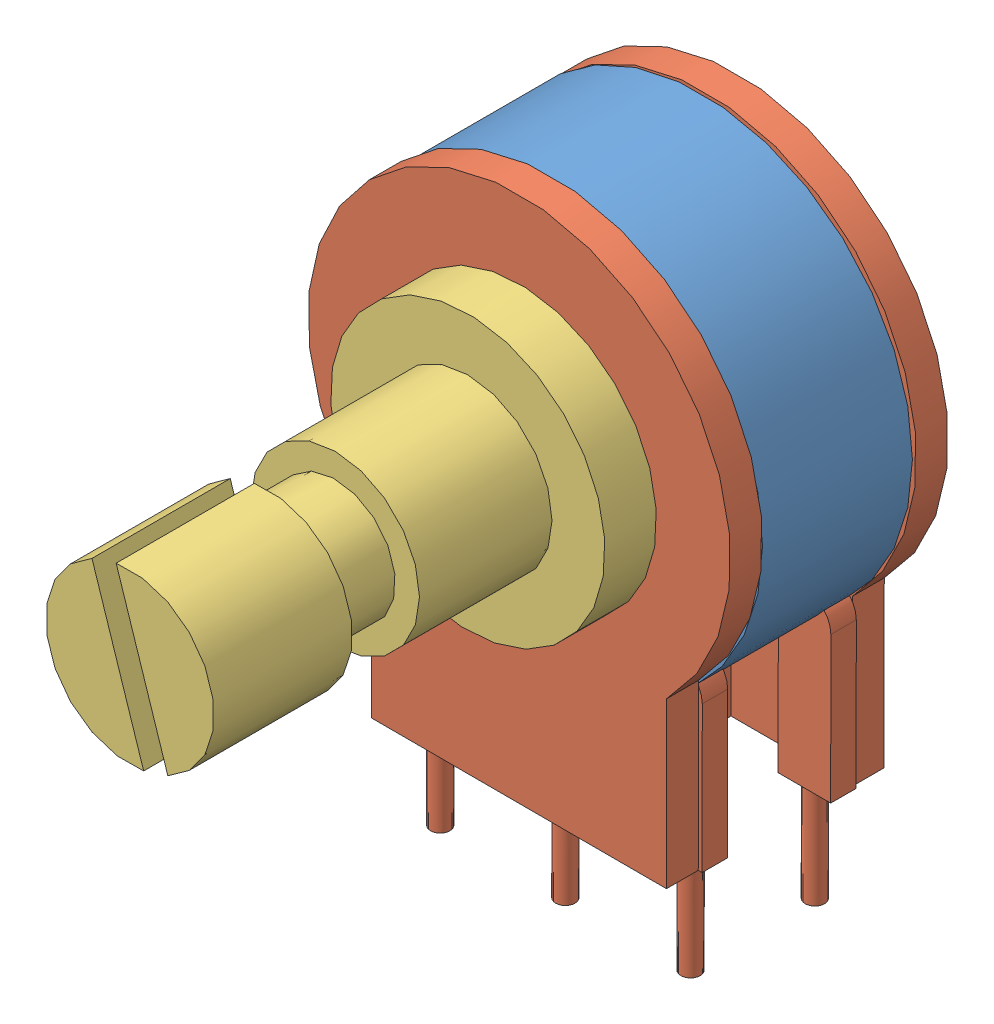
SolidWorks assembly Dual Pot Normal, configuration Default. Lengths in mm.
Overall size (17.1 25.22 24.09).
4 component instances, 3 part files, 1 mates.
Components (placement in the parent):
- Body1-1: Body1 [Default] at (-8.6298 0.3105 1.1044) size (16.9 16.9 6.02)
- Waffer1-1: Waffer1 [Default] at (-8.4673 -2.4617 -0.1338) x (0.999999 -0.001262 0) z (0 0 1) size (16.9 25.2 2.29)
- Waffer1-2: Waffer1 [Default] at (-8.6333 -2.4615 8.3944) x (-0.999999 0.001262 0) z (0 0 -1) size (16.9 25.2 2.29)
- Shaft1-1: Shaft1 [Default] at (-8.6298 0.3105 8.3944) x (-0.95047 -0.310817 0) z (0 0 1) size (10.97 10.97 15.56)
Mates (geometry in assembly coordinates):
- Coincident15: coincident aligned: plane of Waffer1-1 through (-14.3759 -12.1823 1.1362) normal (-0.001262 -0.999999 0); plane of Waffer1-2 through (-2.7493 -12.1969 7.1244) normal (-0.001262 -0.999999 0)
